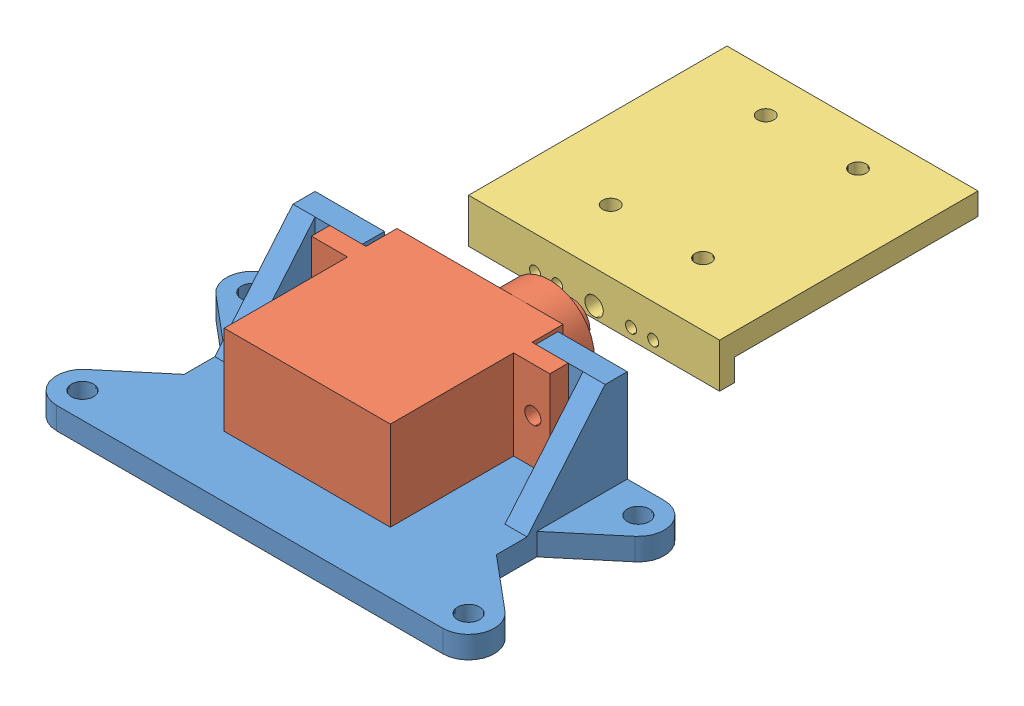
SolidWorks assembly Camera Mount Assembly, configuration Default. Lengths in mm.
Overall size (59.3 15.6 76.5).
3 component instances, 3 part files, 8 mates.
Components (placement in the parent):
- Servo Mounting Bracket-1: Servo Mounting Bracket [Default] at (14.2389 21.8039 46.0964) size (59.3 15.6 30)
- Continuous Rotation Servo-1: Continuous Rotation Servo [Default] at (2.9889 25.3039 68.2964) x (0 1 0) z (-1 0 0) size (12.1 30.7 32.3)
- Camera Mounting Bracket-1: Camera Mounting Bracket [Default] at (36.3889 29.8539 34.5964) x (-1 0 0) z (0 -1 0) size (34 35 6)
Mates (geometry in assembly coordinates):
- Coincident4: coincident anti-aligned: plane of Servo Mounting Bracket-1 through (14.2389 21.8039 49.0964) normal (0 0 1); plane of Continuous Rotation Servo-1 through (30.3889 37.4039 49.0964) normal (0 0 -1)
- Parallel3: parallel aligned: plane of Servo Mounting Bracket-1 through (-6.9111 37.4039 49.0964) normal (0 1 0); plane of Continuous Rotation Servo-1 through (2.9889 37.4039 68.2964) normal (0 1 0)
- Coincident13: coincident anti-aligned: plane of Servo Mounting Bracket-1 through (14.2389 21.8039 49.0964) normal (0 0 1); plane of Continuous Rotation Servo-1 through (2.9889 37.4039 49.0964) normal (0 0 -1)
- Concentric14: concentric anti-aligned: cylinder of Servo Mounting Bracket-1 through (0.3889 31.3539 46.0964) axis (0 0 1) radius 1.1; cylinder of Continuous Rotation Servo-1 through (0.3889 31.3539 68.2964) axis (0 0 -1) radius 1.1
- Concentric15: concentric anti-aligned: cylinder of Servo Mounting Bracket-1 through (28.0889 31.3539 46.0964) axis (0 0 1) radius 1.1; cylinder of Continuous Rotation Servo-1 through (28.0889 31.3539 68.2964) axis (0 0 -1) radius 1.1
- Concentric16: concentric: cylinder of Continuous Rotation Servo-1 through (19.3889 31.3539 30.7233) axis (0 0 1) radius 2.43; cylinder of Camera Mounting Bracket-1 through (19.3889 31.3539 34.5964) axis (0 0 -1) radius 1.25
- Distance1: distance = 3 mm: plane of Camera Mounting Bracket-1 through (2.3889 29.8539 34.5964) normal (0 0 1); plane of Continuous Rotation Servo-1 through (2.9889 25.3039 37.5964) normal (0 0 -1)
- Parallel4: parallel aligned: plane of Continuous Rotation Servo-1 through (2.9889 37.4039 68.2964) normal (0 1 0); plane of Camera Mounting Bracket-1 through (2.3889 35.8539 34.5964) normal (0 1 0)
